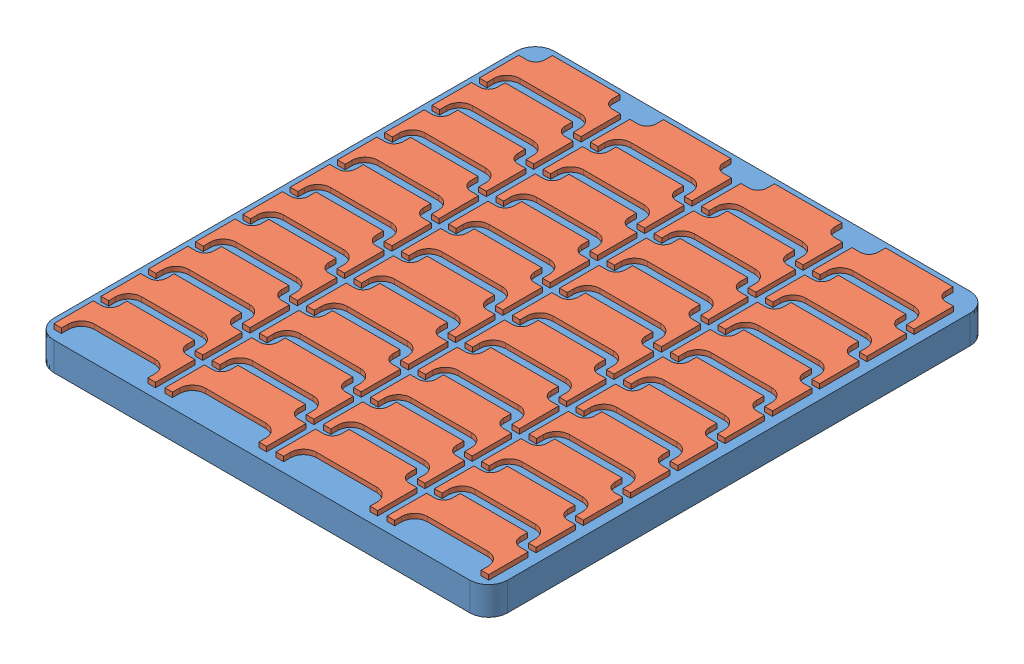
SolidWorks assembly Mold Assembly, configuration Valor predeterminado. Lengths in mm.
Overall size (96 7 105.85).
41 component instances, 2 part files, 7 mates.
Components (placement in the parent):
- Surface Mold - TrackTooth-1: Surface Mold - TrackTooth [Valor predeterminado] at origin size (96 6 105.85)
- TrackTooth Surface-1: TrackTooth Surface [Valor predeterminado] at (35.25 2.5 45) x (-1 0 0) z (0 0 -1) size (21.5 3 11.85)
- TrackTooth Surface-2: TrackTooth Surface [Valor predeterminado] at (35.25 2.5 35) x (-1 0 0) z (0 0 -1) size (21.5 3 11.85)
- TrackTooth Surface-3: TrackTooth Surface [Valor predeterminado] at (35.25 2.5 25) x (-1 0 0) z (0 0 -1) size (21.5 3 11.85)
- TrackTooth Surface-4: TrackTooth Surface [Valor predeterminado] at (35.25 2.5 15) x (-1 0 0) z (0 0 -1) size (21.5 3 11.85)
- TrackTooth Surface-5: TrackTooth Surface [Valor predeterminado] at (35.25 2.5 5) x (-1 0 0) z (0 0 -1) size (21.5 3 11.85)
- TrackTooth Surface-6: TrackTooth Surface [Valor predeterminado] at (35.25 2.5 -5) x (-1 0 0) z (0 0 -1) size (21.5 3 11.85)
- TrackTooth Surface-7: TrackTooth Surface [Valor predeterminado] at (11.75 2.5 45) x (-1 0 0) z (0 0 -1) size (21.5 3 11.85)
- TrackTooth Surface-8: TrackTooth Surface [Valor predeterminado] at (11.75 2.5 35) x (-1 0 0) z (0 0 -1) size (21.5 3 11.85)
- TrackTooth Surface-9: TrackTooth Surface [Valor predeterminado] at (11.75 2.5 25) x (-1 0 0) z (0 0 -1) size (21.5 3 11.85)
- TrackTooth Surface-10: TrackTooth Surface [Valor predeterminado] at (11.75 2.5 15) x (-1 0 0) z (0 0 -1) size (21.5 3 11.85)
- TrackTooth Surface-11: TrackTooth Surface [Valor predeterminado] at (11.75 2.5 5) x (-1 0 0) z (0 0 -1) size (21.5 3 11.85)
- TrackTooth Surface-12: TrackTooth Surface [Valor predeterminado] at (11.75 2.5 -5) x (-1 0 0) z (0 0 -1) size (21.5 3 11.85)
- TrackTooth Surface-13: TrackTooth Surface [Valor predeterminado] at (-11.75 2.5 45) x (-1 0 0) z (0 0 -1) size (21.5 3 11.85)
- TrackTooth Surface-14: TrackTooth Surface [Valor predeterminado] at (-11.75 2.5 35) x (-1 0 0) z (0 0 -1) size (21.5 3 11.85)
- TrackTooth Surface-15: TrackTooth Surface [Valor predeterminado] at (-11.75 2.5 25) x (-1 0 0) z (0 0 -1) size (21.5 3 11.85)
- TrackTooth Surface-16: TrackTooth Surface [Valor predeterminado] at (-11.75 2.5 15) x (-1 0 0) z (0 0 -1) size (21.5 3 11.85)
- TrackTooth Surface-17: TrackTooth Surface [Valor predeterminado] at (-11.75 2.5 5) x (-1 0 0) z (0 0 -1) size (21.5 3 11.85)
- TrackTooth Surface-18: TrackTooth Surface [Valor predeterminado] at (-11.75 2.5 -5) x (-1 0 0) z (0 0 -1) size (21.5 3 11.85)
- TrackTooth Surface-19: TrackTooth Surface [Valor predeterminado] at (-35.25 2.5 45) x (-1 0 0) z (0 0 -1) size (21.5 3 11.85)
- TrackTooth Surface-20: TrackTooth Surface [Valor predeterminado] at (-35.25 2.5 35) x (-1 0 0) z (0 0 -1) size (21.5 3 11.85)
- TrackTooth Surface-21: TrackTooth Surface [Valor predeterminado] at (-35.25 2.5 25) x (-1 0 0) z (0 0 -1) size (21.5 3 11.85)
- TrackTooth Surface-22: TrackTooth Surface [Valor predeterminado] at (-35.25 2.5 15) x (-1 0 0) z (0 0 -1) size (21.5 3 11.85)
- TrackTooth Surface-23: TrackTooth Surface [Valor predeterminado] at (-35.25 2.5 5) x (-1 0 0) z (0 0 -1) size (21.5 3 11.85)
- TrackTooth Surface-24: TrackTooth Surface [Valor predeterminado] at (-35.25 2.5 -5) x (-1 0 0) z (0 0 -1) size (21.5 3 11.85)
- TrackTooth Surface-25: TrackTooth Surface [Valor predeterminado] at (35.25 2.5 -15) x (-1 0 0) z (0 0 -1) size (21.5 3 11.85)
- TrackTooth Surface-26: TrackTooth Surface [Valor predeterminado] at (35.25 2.5 -25) x (-1 0 0) z (0 0 -1) size (21.5 3 11.85)
- TrackTooth Surface-27: TrackTooth Surface [Valor predeterminado] at (35.25 2.5 -35) x (-1 0 0) z (0 0 -1) size (21.5 3 11.85)
- TrackTooth Surface-28: TrackTooth Surface [Valor predeterminado] at (11.75 2.5 -15) x (-1 0 0) z (0 0 -1) size (21.5 3 11.85)
- TrackTooth Surface-29: TrackTooth Surface [Valor predeterminado] at (11.75 2.5 -25) x (-1 0 0) z (0 0 -1) size (21.5 3 11.85)
- TrackTooth Surface-30: TrackTooth Surface [Valor predeterminado] at (11.75 2.5 -35) x (-1 0 0) z (0 0 -1) size (21.5 3 11.85)
- TrackTooth Surface-31: TrackTooth Surface [Valor predeterminado] at (-11.75 2.5 -15) x (-1 0 0) z (0 0 -1) size (21.5 3 11.85)
- TrackTooth Surface-32: TrackTooth Surface [Valor predeterminado] at (-11.75 2.5 -25) x (-1 0 0) z (0 0 -1) size (21.5 3 11.85)
- TrackTooth Surface-33: TrackTooth Surface [Valor predeterminado] at (-11.75 2.5 -35) x (-1 0 0) z (0 0 -1) size (21.5 3 11.85)
- TrackTooth Surface-34: TrackTooth Surface [Valor predeterminado] at (-35.25 2.5 -15) x (-1 0 0) z (0 0 -1) size (21.5 3 11.85)
- TrackTooth Surface-35: TrackTooth Surface [Valor predeterminado] at (-35.25 2.5 -25) x (-1 0 0) z (0 0 -1) size (21.5 3 11.85)
- TrackTooth Surface-36: TrackTooth Surface [Valor predeterminado] at (-35.25 2.5 -35) x (-1 0 0) z (0 0 -1) size (21.5 3 11.85)
- TrackTooth Surface-37: TrackTooth Surface [Valor predeterminado] at (35.25 2.5 -45) x (-1 0 0) z (0 0 -1) size (21.5 3 11.85)
- TrackTooth Surface-38: TrackTooth Surface [Valor predeterminado] at (11.75 2.5 -45) x (-1 0 0) z (0 0 -1) size (21.5 3 11.85)
- TrackTooth Surface-39: TrackTooth Surface [Valor predeterminado] at (-11.75 2.5 -45) x (-1 0 0) z (0 0 -1) size (21.5 3 11.85)
- TrackTooth Surface-40: TrackTooth Surface [Valor predeterminado] at (-35.25 2.5 -45) x (-1 0 0) z (0 0 -1) size (21.5 3 11.85)
Mates (geometry in assembly coordinates):
- Distance2: distance = 1 mm anti-aligned: plane of Dente Esteira - Engrenagem-1 through (40.627 0.5 32.368) normal (0 -1 0); plane of Molde Superfície Dente Esteira-1 through (0 3 0) normal (0 1 0)
- Parallel1: parallel aligned: plane of Molde Superfície Dente Esteira-1 through (-48 3 -52.925) normal (-1 0 0); plane of Dente Esteira - Engrenagem-1 through (24 3.16 32.368) normal (-1 0 0)
- Distance3: distance = 3 mm aligned: plane of Dente Esteira - Engrenagem-1 through (47 3.16 32.368) normal (1 0 0); plane of Molde Superfície Dente Esteira-1 through (48 3 -52.925) normal (1 0 0)
- Distance5: distance = 5 mm: line of Dente Esteira - Engrenagem-1 through (46.25 5.82 44.218) axis (-1 0 0); plane of Molde Superfície Dente Esteira-1 through (-48 3 52.925) normal (0 0 1)
- Distance6: distance = 2 mm anti-aligned: plane of Superfície Dente Esteira-1 through (41.64 1 49.465) normal (0 -1 0); plane of Molde Superfície Dente Esteira-1 through (0 3 0) normal (0 1 0)
- Distance8: distance = 2 mm aligned: plane of Superfície Dente Esteira-1 through (46 4 50.925) normal (0 0 1); plane of Molde Superfície Dente Esteira-1 through (-48 3 52.925) normal (0 0 1)
- Distance9: distance = 2 mm aligned: plane of Superfície Dente Esteira-1 through (46 4 50.925) normal (1 0 0); plane of Molde Superfície Dente Esteira-1 through (48 3 -52.925) normal (1 0 0)
